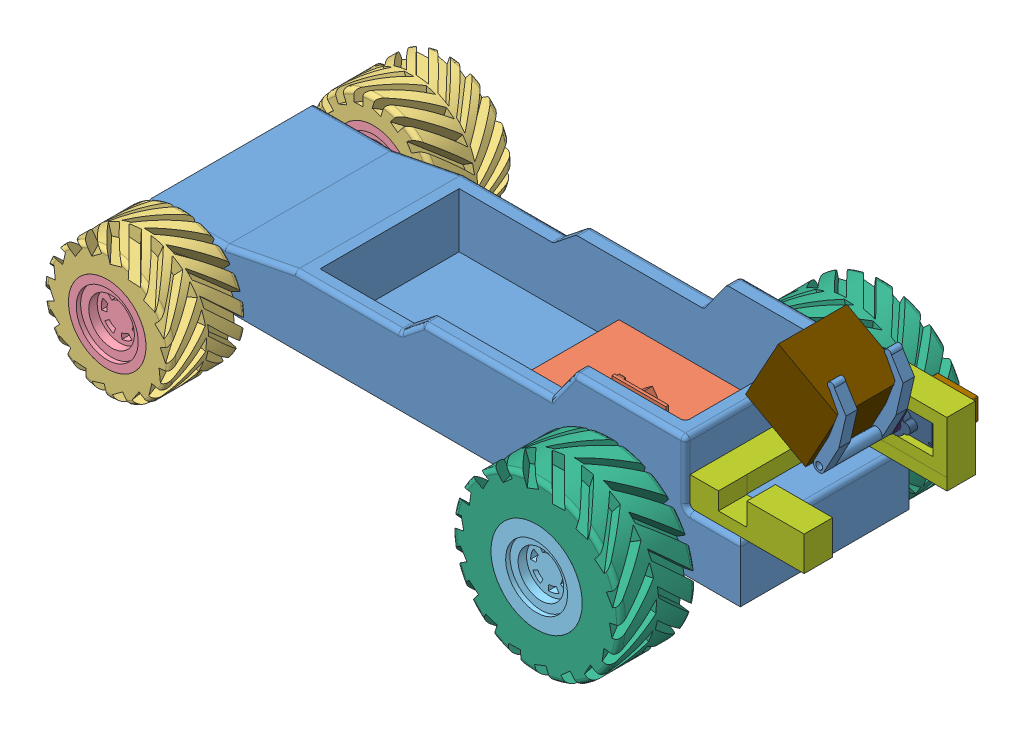
SolidWorks assembly Rover Assembly - Mission 1, configuration Default. Lengths in mm.
Overall size (375.88 149.93 194.02).
30 component instances, 20 part files, 22 mates.
Components (placement in the parent):
- Rover Body-1: Rover Body [Default] at (344.4949 122.428 170.6048) size (330.2 66.04 119.38)
- Arduino- Motor Shield-1: Arduino- Motor Shield [Default] at (168.705 155.448 219.6335) x (0 0 1) z (0 -1 0) size (53.34 68.58 25.4)
- Front Wheel Assembly-1: Front Wheel Assembly [Default] at (-53.7503 89.6283 164.2176) x (0.997993 -0.063319 0) z (0 0 1) size (71.72 71.61 42.52)
  - Tire 1-2: Tire 1 [Default] at (19.9119 41.7643 105.936) size (71.72 71.61 42.52)
  - Front Wheel Hub-1: Front Wheel Hub [Default] at (19.9119 41.7643 126.891) size (43.18 43.18 41.91)
- Front Wheel Assembly-2: Front Wheel Assembly [Default] at (-9.6863 89.1036 269.8027) x (-0.999218 -0.039537 0) z (0 0 -1) size (71.72 71.61 42.52)
  - Tire 1-2: Tire 1 [Default] at (19.9119 41.7643 105.936) size (71.72 71.61 42.52)
  - Front Wheel Hub-1: Front Wheel Hub [Default] at (19.9119 41.7643 126.891) size (43.18 43.18 41.91)
- Rear Tire Assembly-1: Rear Tire Assembly [Default] at (171.7555 66.6662 202.9618) x (0.99964 0.026848 0) z (0 0 1) size (94.56 94.48 42.49)
  - Rear Wheel Hub-1: Rear Wheel Hub [Default] at (39.9984 62.3303 90.5124) x (0.280155 -0.959955 0) z (0 0 1) size (50.8 50.8 41.91)
  - Rear Tire-2: Rear Tire [Default] at (39.9984 62.3303 69.5574) size (94.56 94.48 42.49)
- Rear Tire Assembly-2: Rear Tire Assembly [Default] at (263.4815 78.7475 232.4452) x (-0.9725 -0.232904 0) z (0 0 -1) size (94.56 94.48 42.49)
  - Rear Wheel Hub-1: Rear Wheel Hub [Default] at (39.9984 62.3303 90.5124) x (0.280155 -0.959955 0) z (0 0 1) size (50.8 50.8 41.91)
  - Rear Tire-2: Rear Tire [Default] at (39.9984 62.3303 69.5574) size (94.56 94.48 42.49)
- Payload Dump Assembly-1: Payload Dump Assembly [Default] at (322.5158 116.0548 289.3283) x (-1 0 0) z (0 0 -1) size (63.5 36.7 104.97)
  - Payload Dump Part 1-1: Payload Dump Part 1 [Default] at (47.6797 37.6452 74.9084) size (63.5 35.56 95.25)
  - Servo Motor .step-1: Servo Motor .step [Default] at (12.5966 90.0691 118.4584) x (-1 0 0) z (0 0 -1) size (32.76 20.08 39.19)
    - CenterCover.step-1: CenterCover.step [Default] at (-22.9609 -17.25 -6.1) size (22.75 12.2 26.35)
    - UnderCover.step-1: UnderCover.step [Default] at (-22.9609 0 -6.1) x (1 0 0) z (0 0 -1) size (22.75 12.2 8.4)
    - UpCover.step-1: UpCover.step [Default] at (-22.9609 -17.25 -6.1) x (1 0 0) z (0 0 -1) size (32.3 12.2 14.95)
    - Motor.step-1: Motor.step [Default] at (-21.8609 -2.15 -6.1) x (-1 0 0) z (0 0 1) size (20.9 10.57 17.7)
    - DoubleGear.step-1: DoubleGear.step [Default] at (-28.3359 -24.2 -6.1) x (-0.559274 0 -0.828983) z (0.828983 0 -0.559274) size (18.51 9.78 13.91)
    - Gear(3.5mm).step-1: Gear(3.5mm).step [Default] at (-28.3359 -19.8 -6.1) x (0.988403 0 -0.151851) z (-0.151851 0 -0.988403) size (10.03 9.9 4.97)
    - Gear(3mm).step-1: Gear(3mm).step [Default] at (-22.0328 -18.375 -6.1) x (0.198669 0 -0.980067) z (0.980067 0 0.198669) size (4.09 9.58 9.64)
    - Gear(4mm).step-1: Gear(4mm).step [Default] at (-22.0328 -21.575 -6.1) x (0.522456 0 0.852666) z (-0.852666 0 0.522456) size (8.4 9.89 9.4)
    - Part2^ServoMotor.step-1: Part2^ServoMotor.step [Default] at (-21.8581 -17.2 -5.9293) x (-0.999471 0 0.032512) z (0 -1 0) size (2 1.66 1.98)
    - Angle.step-1: Angle.step [Default] at (-28.3359 -33.5 -6.1) x (-0.519685 0 -0.854358) z (0 1 0) size (9.91 11.74 17.48)
- Payload Block-1: Payload Block [Default] at (239.737 189.6215 189.761) x (0.876689 -0.481058 0) z (0 0 1) size (38.1 38.1 38.1)
- Payload Arm-1: Payload Arm [Default] at (281.5834 176.4239 196.9198) x (0.470924 0.882174 0) z (0 0 1) size (44.97 18.98 38.1)
- RF-5V-1: RF-5V [Default] at (314.995 263.448 235.4726) x (-1 0 0) z (0 0 -1) size (30 17.61 10.46)
Mates (geometry in assembly coordinates):
- Parallel1: parallel anti-aligned: plane of Rover Body-1 through (344.4949 130.048 170.6048) normal (0 1 0); plane of Arduino- Motor Shield-1 through (168.705 130.048 219.6335) normal (0 -1 0)
- Parallel2: parallel aligned: plane of Rover Body-1 through (344.4949 122.428 170.6048) normal (0 0 -1); plane of Arduino- Motor Shield-1 through (202.995 130.048 192.9635) normal (0 0 -1)
- Coincident3: coincident anti-aligned: plane of Rover Body-1 through (344.4949 130.048 170.6048) normal (0 1 0); plane of Arduino- Motor Shield-1 through (168.705 130.048 219.6335) normal (0 -1 0)
- Parallel3: parallel anti-aligned: plane of Rover Body-1 through (344.4949 122.428 170.6048) normal (0 0 -1); plane of Rear Tire Assembly-2/Rear Wheel Hub-1 through (210.0661 130.048 162.8878) normal (0 0 1)
- Concentric1: concentric aligned: cylinder of Rover Body-1 through (210.0661 130.048 157.9048) axis (0 0 1) radius 4.445; cylinder of Rear Tire Assembly-2/Rear Wheel Hub-1 through (210.0661 130.048 143.0758) axis (0 0 1) radius 4.445
- Concentric2: concentric aligned: cylinder of Rover Body-1 through (210.0661 130.048 277.2848) axis (0 0 -1) radius 4.445; cylinder of Rear Tire Assembly-1/Rear Wheel Hub-1 through (210.0661 130.048 292.3312) axis (0 0 -1) radius 4.445
- Concentric3: concentric aligned: cylinder of Rover Body-1 through (-31.2339 130.048 157.9048) axis (0 0 1) radius 4.445; cylinder of Front Wheel Assembly-2/Front Wheel Hub-1 through (-31.2339 130.048 144.0547) axis (0 0 1) radius 4.445
- Concentric4: concentric aligned: cylinder of Rover Body-1 through (-31.2339 130.048 277.2848) axis (0 0 -1) radius 4.445; cylinder of Front Wheel Assembly-1/Front Wheel Hub-1 through (-31.2339 130.048 289.9655) axis (0 0 -1) radius 4.445
- Parallel4: parallel anti-aligned: plane of Rover Body-1 through (243.0861 153.7 264.5848) normal (1 0 0); plane of Payload Dump Assembly-1/Payload Dump Part 1-1 through (243.0861 189.26 166.7948) normal (-1 0 0)
- Parallel5: parallel aligned: plane of Rover Body-1 through (273.5661 153.7 264.5848) normal (0 1 0); plane of Payload Dump Assembly-1/Payload Dump Part 1-1 through (243.0861 169.702 166.7948) normal (0 1 0)
- Coincident10: coincident anti-aligned: plane of Rover Body-1 through (243.0861 153.7 264.5848) normal (1 0 0); plane of Payload Dump Assembly-1/Payload Dump Part 1-1 through (243.0861 189.26 166.7948) normal (-1 0 0)
- Coincident11: coincident anti-aligned: plane of Rover Body-1 through (273.5661 153.7 264.5848) normal (0 1 0); plane of Payload Dump Assembly-1/Payload Dump Part 1-1 through (274.8361 153.7 214.4198) normal (0 -1 0)
- Parallel6: parallel aligned: line of Rover Body-1 through (-56.6339 122.428 264.5848) axis (1 0 0); line of Payload Dump Assembly-1/Payload Dump Part 1-1 through (243.0861 153.7 262.0448) axis (1 0 0)
- Parallel8: parallel aligned: plane of Rover Body-1 through (344.4949 122.428 264.5848) normal (0 0 1); plane of Payload Block-1 through (248.888 202.3018 228.6698) normal (0 0 1)
- Coincident23: coincident aligned: line of Rover Body-1 through (245.6261 153.7 262.0448) axis (1 0 0); line of Payload Dump Assembly-1/Payload Dump Part 1-1 through (243.0861 153.7 262.0448) axis (1 0 0)
- Parallel13: parallel anti-aligned: plane of Payload Dump Assembly-1/Servo Motor .step-1/Angle.step-1 through (281.5834 176.4239 190.5698) normal (0 0 1); plane of Payload Arm-1 through (281.5834 176.4239 190.5698) normal (0 0 -1)
- Concentric5: concentric aligned: cylinder of Payload Dump Assembly-1/Servo Motor .step-1/Angle.step-1 through (281.5834 176.4239 189.0698) axis (0 0 1) radius 1.325; cylinder of Payload Arm-1 through (281.5834 176.4239 222.3198) axis (0 0 1) radius 1.905
- Coincident25: coincident anti-aligned: plane of Payload Dump Assembly-1/Servo Motor .step-1/Angle.step-1 through (281.5834 176.4239 190.5698) normal (0 0 1); plane of Payload Arm-1 through (281.5834 176.4239 190.5698) normal (0 0 -1)
- Parallel14: parallel aligned: plane of Payload Block-1 through (248.888 202.3018 228.6698) normal (0 0 1); plane of Payload Arm-1 through (281.5834 176.4239 228.6698) normal (0 0 1)
- Coincident33: coincident anti-aligned: plane of Arduino- Motor Shield-1 through (168.705 155.448 219.6335) normal (0 1 0); plane of RF-5V-1 through (202.995 155.448 235.4726) normal (0 -1 0)
- Parallel18: parallel anti-aligned: plane of Rover Body-1 through (31.8594 188.468 256.6758) normal (0 0 -1); plane of RF-5V-1 through (187.995 162.248 235.4726) normal (0 0 1)
- Coincident35: coincident aligned: line of Arduino- Motor Shield-1 through (202.995 155.448 246.3035) axis (0 0 -1); line of RF-5V-1 through (202.995 155.448 235.4726) axis (0 0 -1)
